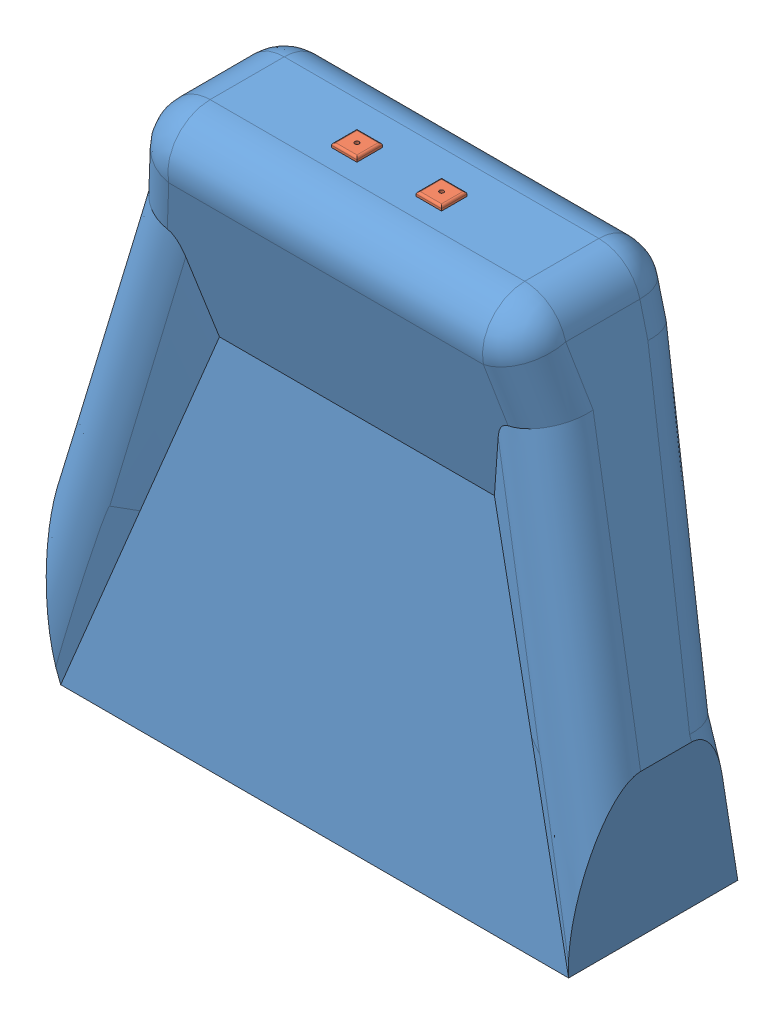
SolidWorks assembly Back Seat Assembly, configuration Default. Lengths in mm.
Overall size (704.87 640.09 273.14).
3 component instances, 2 part files, 8 mates.
Components (placement in the parent):
- Back Seat-1: Back Seat [Default] at origin size (704.87 635.01 273.14)
- Back Seat Connection-1: Back Seat Connection [Default] at (-50.8 635 101.6) size (30.48 102.87 30.48)
- Back Seat Connection-2: Back Seat Connection [Default] at (50.8 635 101.6) x (-1 0 0) z (0 0 -1) size (30.48 102.87 30.48)
Mates (geometry in assembly coordinates):
- Coincident3: coordinate: point of Back Seat-1
- Coincident4: coincident aligned: plane of Back Seat-1 through (0 0 0) normal (0 0 1)
- Concentric1: concentric anti-aligned: circle of Back Seat-1; circle of Back Seat Connection-1
- Coincident6: coincident anti-aligned: plane of Back Seat-1 through (-50.8 537.21 101.6) normal (0 1 0); plane of Back Seat Connection-1 through (-50.8 537.21 101.6) normal (0 -1 0)
- Parallel1: parallel aligned: plane of Back Seat Connection-1 through (-50.8 635 101.6) normal (0 0 1)
- Concentric2: concentric aligned: circle of Back Seat-1; circle of Back Seat Connection-2
- Coincident9: coincident anti-aligned: plane of Back Seat-1 through (50.8 537.21 101.6) normal (0 1 0); plane of Back Seat Connection-2 through (50.8 537.21 101.6) normal (0 -1 0)
- Parallel3: parallel anti-aligned: plane of Back Seat Connection-2 through (50.8 635 101.6) normal (0 0 -1)
